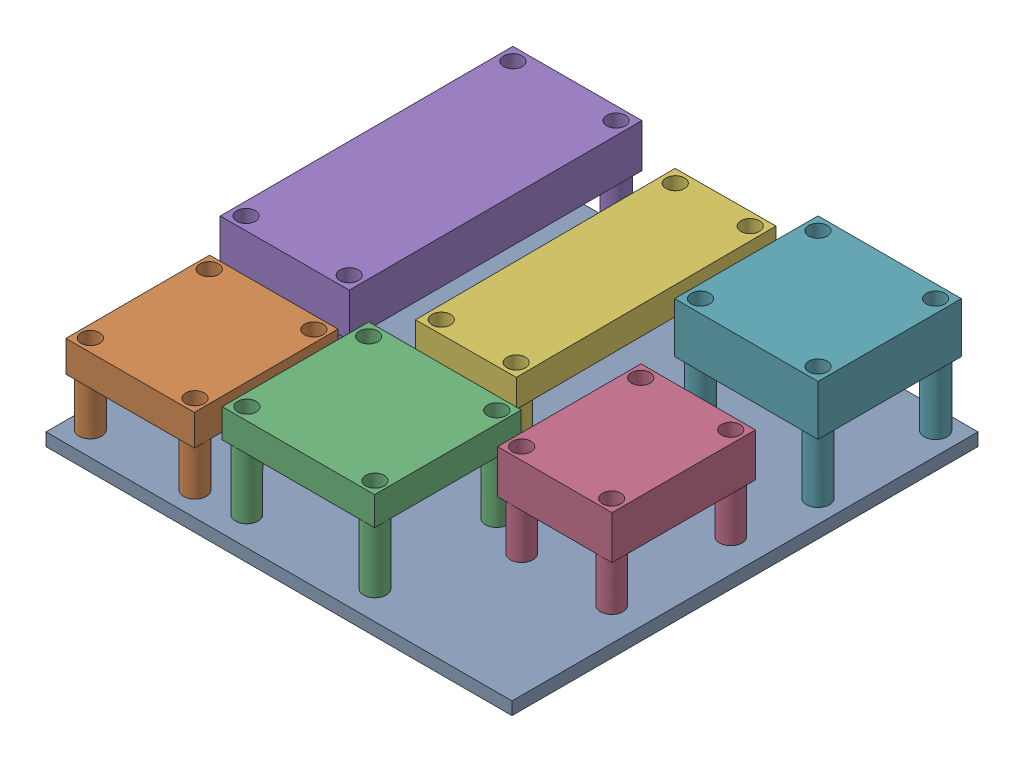
SolidWorks assembly ElectricBoard, configuration Default. Lengths in mm.
Overall size (82.55 22.45 82.55).
7 component instances, 7 part files, 6 mates.
Components (placement in the parent):
- Base-1: Base [Default] at (-6.5354 -37.2691 22.5104) size (82.55 2.26 82.55)
- BN008x 900F-2: BN008x 900F [Default] at (-89.6352 -26.4233 14.0243) x (0.999999 0 -0.001527) z (0.001527 0 0.999999) size (22.73 14.07 25.5)
- QWIIC OpenLog-2: QWIIC OpenLog [Default] at (-85.5536 -23.5277 21.6575) size (27 16.56 25.98)
- MAX 17046-2: MAX 17046 [Default] at (-57.3424 -26.2963 1.2366) size (20.27 16.38 25.4)
- RP2-B2-1: RP2-B2 [Default] at (-112.4446 -23.7817 -6.5902) x (-0.002017 0 -0.999998) z (0.999998 0 -0.002017) size (51.94 18.92 22.81)
- BME680-1: BME680 [Default] at (-76.1412 -23.1467 -28.0674) x (0.999988 0 -0.00483) z (0.00483 0 0.999988) size (17.78 16.76 46.23)
- PA101-1: PA101 [Default] at (-52.8253 -23.7055 -29.9258) size (25.4 20.19 25.4)
Mates (geometry in assembly coordinates):
- Coincident1: coincident anti-aligned: plane of Base-1 through (-6.5354 -35.0085 22.5104) normal (0 1 0); circle of BN008x 900F-2
- Coincident2: coincident anti-aligned: plane of Base-1 through (-6.5354 -35.0085 22.5104) normal (0 1 0); circle of QWIIC OpenLog-2
- Coincident3: coincident anti-aligned: plane of Base-1 through (-6.5354 -35.0085 22.5104) normal (0 1 0); circle of MAX 17046-2
- Coincident4: coincident anti-aligned: plane of Base-1 through (-6.5354 -35.0085 22.5104) normal (0 1 0); circle of PA101-1
- Coincident5: coincident anti-aligned: plane of Base-1 through (-6.5354 -35.0085 22.5104) normal (0 1 0); circle of BME680-1
- Coincident6: coincident anti-aligned: plane of Base-1 through (-6.5354 -35.0085 22.5104) normal (0 1 0); circle of RP2-B2-1
